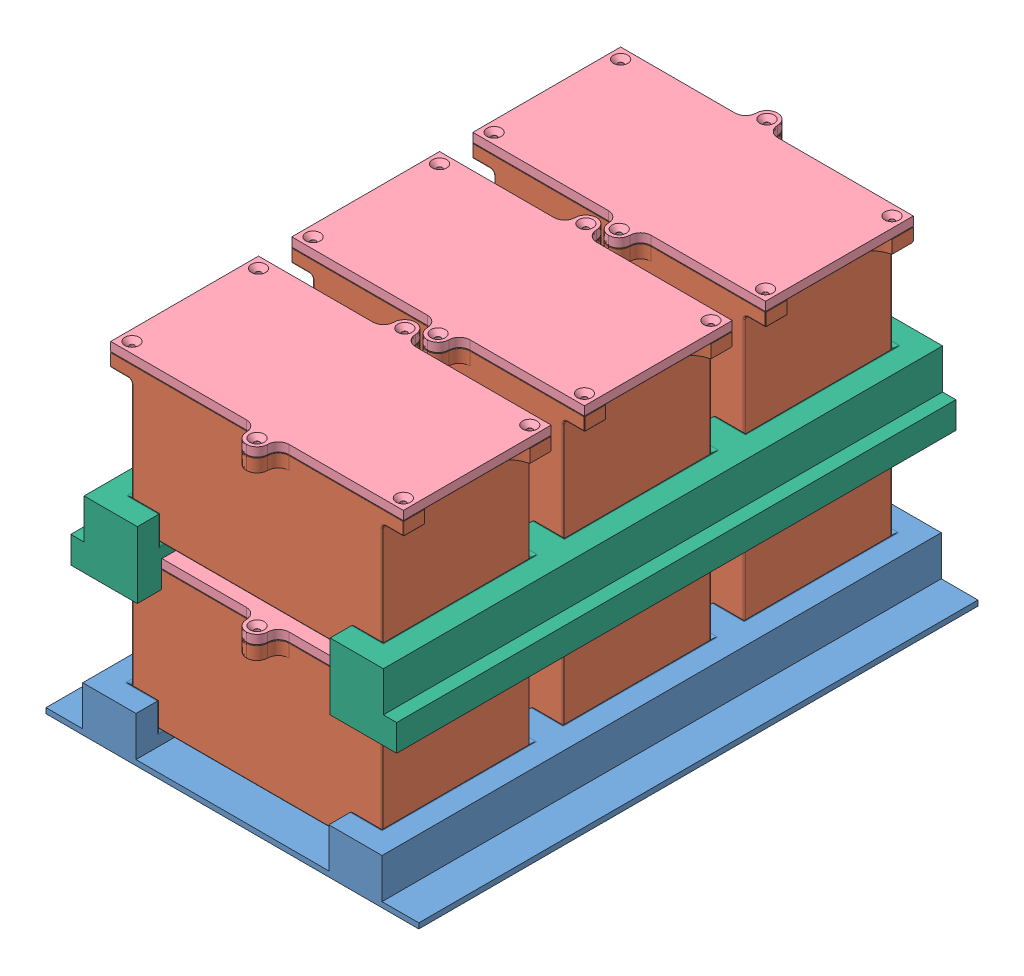
SolidWorks assembly Assembly, configuration Standard. Lengths in mm.
Overall size (140 124 210).
32 component instances, 6 part files, 9 mates.
Components (placement in the parent):
- Bodycube_lowerpart-1: Bodycube_lowerpart [Standard] at origin size (140 17 210)
- organcube-1: organcube [Standard] at (0 9.5 68) x (0 0 -1) z (0 1 0) size (71.5 109.9 56)
  - Organcube_box-1: Organcube_box [Standard] at origin size (71.5 109.9 54)
  - Organcube_middle-1: Organcube_middle [Standard] x (0 1 0) z (1 0 0) size (80 40 32)
  - Organcube_top-1: Organcube_top [Standard] at (0 0 53.5) x (1 0 0) z (0 1 0) size (71.5 3.5 109.9)
  - Organcube_seal2-1: Organcube_seal2 [Standard] at (-0.75 0.75 50.5) x (0 1 0) z (1 0 0) size (88.6 1.5 50.2)
- organcube-2: organcube [Standard] at (0 9.5 0) x (0 0 -1) z (0 1 0) size (71.5 109.9 56)
  - Organcube_box-1: Organcube_box [Standard] at origin size (71.5 109.9 54)
  - Organcube_middle-1: Organcube_middle [Standard] x (0 1 0) z (1 0 0) size (80 40 32)
  - Organcube_top-1: Organcube_top [Standard] at (0 0 53.5) x (1 0 0) z (0 1 0) size (71.5 3.5 109.9)
  - Organcube_seal2-1: Organcube_seal2 [Standard] at (-0.75 0.75 50.5) x (0 1 0) z (1 0 0) size (88.6 1.5 50.2)
- organcube-3: organcube [Standard] at (0 9.5 -68) x (0 0 -1) z (0 1 0) size (71.5 109.9 56)
  - Organcube_box-1: Organcube_box [Standard] at origin size (71.5 109.9 54)
  - Organcube_middle-1: Organcube_middle [Standard] x (0 1 0) z (1 0 0) size (80 40 32)
  - Organcube_top-1: Organcube_top [Standard] at (0 0 53.5) x (1 0 0) z (0 1 0) size (71.5 3.5 109.9)
  - Organcube_seal2-1: Organcube_seal2 [Standard] at (-0.75 0.75 50.5) x (0 1 0) z (1 0 0) size (88.6 1.5 50.2)
- Bodycube_top-1: Bodycube_top [Standard] at (0.5 61 0) size (122.4 25 210)
- organcube-4: organcube [Standard] at (0 70.5 68) x (0 0 -1) z (0 1 0) size (71.5 109.9 56)
  - Organcube_box-1: Organcube_box [Standard] at origin size (71.5 109.9 54)
  - Organcube_middle-1: Organcube_middle [Standard] x (0 1 0) z (1 0 0) size (80 40 32)
  - Organcube_top-1: Organcube_top [Standard] at (0 0 53.5) x (1 0 0) z (0 1 0) size (71.5 3.5 109.9)
  - Organcube_seal2-1: Organcube_seal2 [Standard] at (-0.75 0.75 50.5) x (0 1 0) z (1 0 0) size (88.6 1.5 50.2)
- organcube-5: organcube [Standard] at (0 70.5 0) x (0 0 -1) z (0 1 0) size (71.5 109.9 56)
  - Organcube_box-1: Organcube_box [Standard] at origin size (71.5 109.9 54)
  - Organcube_middle-1: Organcube_middle [Standard] x (0 1 0) z (1 0 0) size (80 40 32)
  - Organcube_top-1: Organcube_top [Standard] at (0 0 53.5) x (1 0 0) z (0 1 0) size (71.5 3.5 109.9)
  - Organcube_seal2-1: Organcube_seal2 [Standard] at (-0.75 0.75 50.5) x (0 1 0) z (1 0 0) size (88.6 1.5 50.2)
- organcube-6: organcube [Standard] at (0 70.5 -68) x (0 0 -1) z (0 1 0) size (71.5 109.9 56)
  - Organcube_box-1: Organcube_box [Standard] at origin size (71.5 109.9 54)
  - Organcube_middle-1: Organcube_middle [Standard] x (0 1 0) z (1 0 0) size (80 40 32)
  - Organcube_top-1: Organcube_top [Standard] at (0 0 53.5) x (1 0 0) z (0 1 0) size (71.5 3.5 109.9)
  - Organcube_seal2-1: Organcube_seal2 [Standard] at (-0.75 0.75 50.5) x (0 1 0) z (1 0 0) size (88.6 1.5 50.2)
Mates (geometry in assembly coordinates):
- Deckungsgleich1: coincident aligned: plane of Bodycube_lowerpart-1 through (0 0 0) normal (0 0 1)
- Deckungsgleich2: coincident aligned: plane of Bodycube_lowerpart-1 through (0 0 0) normal (0 1 0)
- Deckungsgleich3: coincident aligned: plane of Bodycube_lowerpart-1 through (0 0 0) normal (1 0 0)
- Deckungsgleich4: coincident anti-aligned: plane of Bodycube_lowerpart-1 through (0 7 0) normal (0 1 0); plane of organcube-1/Organcube_box-1 through (0 7 68) normal (0 -1 0)
- Abstand1: distance = 0.25 mm anti-aligned: plane of organcube-1/Organcube_box-1 through (46.95 59.5 95.75) normal (0 0 1); plane of Bodycube_lowerpart-1 through (-47.2 7 96) normal (0 0 -1)
- Abstand2: distance = 0.25 mm anti-aligned: plane of organcube-1/Organcube_box-1 through (46.95 59.5 95.75) normal (1 0 0); plane of Bodycube_lowerpart-1 through (47.2 7 96) normal (-1 0 0)
- Deckungsgleich7: coincident anti-aligned: plane of organcube-1/Organcube_top-1 through (0 63 68) normal (0 1 0); plane of Bodycube_top-1 through (-0.75 63 0) normal (0 -1 0)
- Abstand3: distance = 0.25 mm anti-aligned: plane of Bodycube_top-1 through (-54.7 63 96) normal (0 0 -1); plane of organcube-1/Organcube_box-1 through (46.95 59.5 95.75) normal (0 0 1)
- Abstand4: distance = 0.25 mm anti-aligned: plane of Bodycube_top-1 through (-54.7 63 40) normal (1 0 0); plane of organcube-1/Organcube_box-1 through (-54.95 54.5 40.25) normal (-1 0 0)
